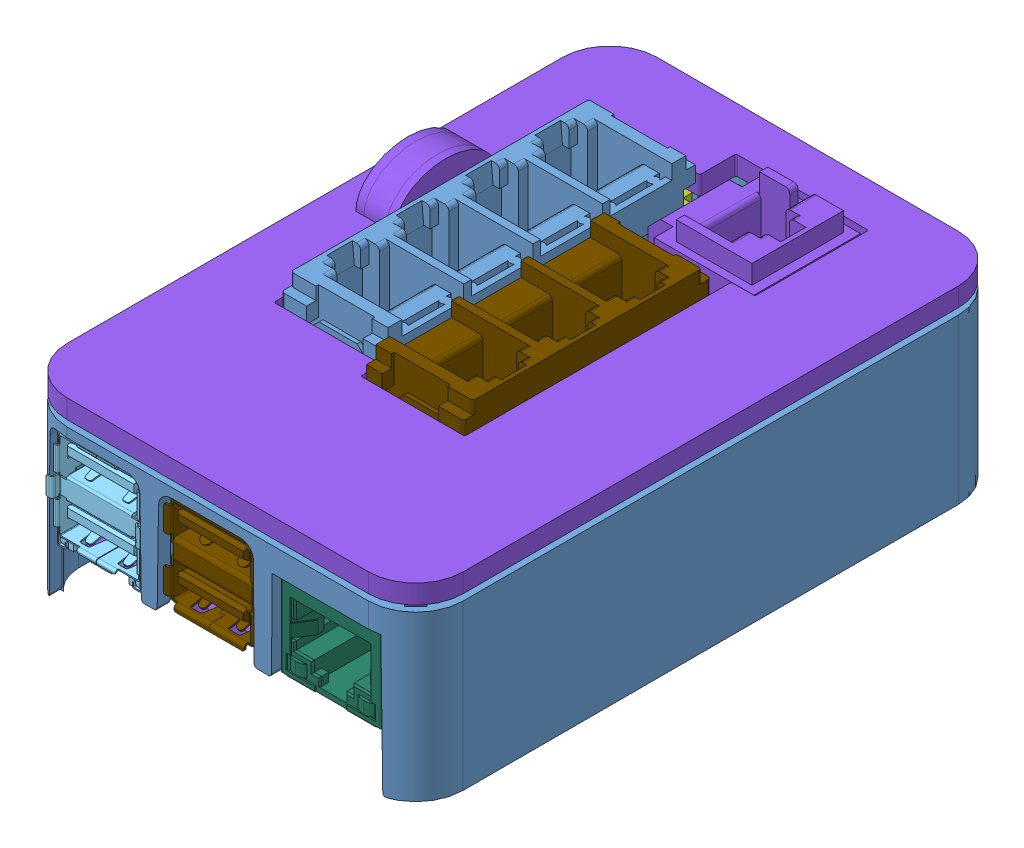
SolidWorks assembly Assemblage_clip_down, configuration Défaut. Lengths in mm.
Overall size (62.75 36.13 93.5).
237 component instances, 44 part files, 9 mates.
Components (placement in the parent):
- RPI4_Canakit_Case-1: RPI4_Canakit_Case [Défaut] at (-18.9096 -7.6584 0) size (62.75 26 93.5)
- Mainboard_Rpi4-1: Mainboard_Rpi4 [Défaut] at (4.6154 9.8935 -38.925) x (0 0 1) z (0 1 0) size (66 57.75 22.04)
  - Mainboard_Rpi4.step-1: Mainboard_Rpi4.step [Défaut] at origin size (66 57.75 22.04)
    - J5.step-1: J5.step [Défaut] at origin size (50.8 7.2 4.95)
      - m20-7812045_asm.step-1: m20-7812045_asm.step [Défaut] at (4.8701 0.0001 -1.7297) x (1 0 0) z (0 1 0) size (50.8 4.95 7.2)
        - M20-78120_MOULD.step-1: M20-78120_MOULD.step [Défaut] at origin size (50.8 4.95 5.08)
        - M20-781_CONTACT.step-1: M20-781_CONTACT.step [Défaut] at (-0.75 1.3 -2.135) size (1.5 2.8 2.83)
        - M20-781_CONTACT.step-2: M20-781_CONTACT.step [Défaut] at (1.79 1.3 -2.135) size (1.5 2.8 2.83)
        - M20-781_CONTACT.step-3: M20-781_CONTACT.step [Défaut] at (4.33 1.3 -2.135) size (1.5 2.8 2.83)
        - M20-781_CONTACT.step-4: M20-781_CONTACT.step [Défaut] at (6.87 1.3 -2.135) size (1.5 2.8 2.83)
        - M20-781_CONTACT.step-5: M20-781_CONTACT.step [Défaut] at (9.41 1.3 -2.135) size (1.5 2.8 2.83)
        - M20-781_CONTACT.step-6: M20-781_CONTACT.step [Défaut] at (11.95 1.3 -2.135) size (1.5 2.8 2.83)
        - M20-781_CONTACT.step-7: M20-781_CONTACT.step [Défaut] at (14.49 1.3 -2.135) size (1.5 2.8 2.83)
        - M20-781_CONTACT.step-8: M20-781_CONTACT.step [Défaut] at (17.03 1.3 -2.135) size (1.5 2.8 2.83)
        - M20-781_CONTACT.step-9: M20-781_CONTACT.step [Défaut] at (19.57 1.3 -2.135) size (1.5 2.8 2.83)
        - M20-781_CONTACT.step-10: M20-781_CONTACT.step [Défaut] at (22.11 1.3 -2.135) size (1.5 2.8 2.83)
        - M20-781_CONTACT.step-11: M20-781_CONTACT.step [Défaut] at (24.65 1.3 -2.135) size (1.5 2.8 2.83)
        - M20-781_CONTACT.step-12: M20-781_CONTACT.step [Défaut] at (27.19 1.3 -2.135) size (1.5 2.8 2.83)
        - M20-781_CONTACT.step-13: M20-781_CONTACT.step [Défaut] at (29.73 1.3 -2.135) size (1.5 2.8 2.83)
        - M20-781_CONTACT.step-14: M20-781_CONTACT.step [Défaut] at (32.27 1.3 -2.135) size (1.5 2.8 2.83)
        - M20-781_CONTACT.step-15: M20-781_CONTACT.step [Défaut] at (34.81 1.3 -2.135) size (1.5 2.8 2.83)
        - M20-781_CONTACT.step-16: M20-781_CONTACT.step [Défaut] at (37.35 1.3 -2.135) size (1.5 2.8 2.83)
        - M20-781_CONTACT.step-17: M20-781_CONTACT.step [Défaut] at (39.89 1.3 -2.135) size (1.5 2.8 2.83)
        - M20-781_CONTACT.step-18: M20-781_CONTACT.step [Défaut] at (42.43 1.3 -2.135) size (1.5 2.8 2.83)
        - M20-781_CONTACT.step-19: M20-781_CONTACT.step [Défaut] at (44.97 1.3 -2.135) size (1.5 2.8 2.83)
        - M20-781_CONTACT.step-20: M20-781_CONTACT.step [Défaut] at (47.51 1.3 -2.135) size (1.5 2.8 2.83)
        - M20-781_CONTACT.step-21: M20-781_CONTACT.step [Défaut] at (0.75 1.3 2.135) x (-1 0 0) z (0 0 -1) size (1.5 2.8 2.83)
        - M20-781_CONTACT.step-22: M20-781_CONTACT.step [Défaut] at (3.29 1.3 2.135) x (-1 0 0) z (0 0 -1) size (1.5 2.8 2.83)
        - M20-781_CONTACT.step-23: M20-781_CONTACT.step [Défaut] at (5.83 1.3 2.135) x (-1 0 0) z (0 0 -1) size (1.5 2.8 2.83)
        - M20-781_CONTACT.step-24: M20-781_CONTACT.step [Défaut] at (8.37 1.3 2.135) x (-1 0 0) z (0 0 -1) size (1.5 2.8 2.83)
        - M20-781_CONTACT.step-25: M20-781_CONTACT.step [Défaut] at (10.91 1.3 2.135) x (-1 0 0) z (0 0 -1) size (1.5 2.8 2.83)
        - M20-781_CONTACT.step-26: M20-781_CONTACT.step [Défaut] at (13.45 1.3 2.135) x (-1 0 0) z (0 0 -1) size (1.5 2.8 2.83)
        - M20-781_CONTACT.step-27: M20-781_CONTACT.step [Défaut] at (15.99 1.3 2.135) x (-1 0 0) z (0 0 -1) size (1.5 2.8 2.83)
        - M20-781_CONTACT.step-28: M20-781_CONTACT.step [Défaut] at (18.53 1.3 2.135) x (-1 0 0) z (0 0 -1) size (1.5 2.8 2.83)
        - M20-781_CONTACT.step-29: M20-781_CONTACT.step [Défaut] at (21.07 1.3 2.135) x (-1 0 0) z (0 0 -1) size (1.5 2.8 2.83)
        - M20-781_CONTACT.step-30: M20-781_CONTACT.step [Défaut] at (23.61 1.3 2.135) x (-1 0 0) z (0 0 -1) size (1.5 2.8 2.83)
        - M20-781_CONTACT.step-31: M20-781_CONTACT.step [Défaut] at (26.15 1.3 2.135) x (-1 0 0) z (0 0 -1) size (1.5 2.8 2.83)
        - M20-781_CONTACT.step-32: M20-781_CONTACT.step [Défaut] at (28.69 1.3 2.135) x (-1 0 0) z (0 0 -1) size (1.5 2.8 2.83)
        - M20-781_CONTACT.step-33: M20-781_CONTACT.step [Défaut] at (31.23 1.3 2.135) x (-1 0 0) z (0 0 -1) size (1.5 2.8 2.83)
        - M20-781_CONTACT.step-34: M20-781_CONTACT.step [Défaut] at (33.77 1.3 2.135) x (-1 0 0) z (0 0 -1) size (1.5 2.8 2.83)
        - M20-781_CONTACT.step-35: M20-781_CONTACT.step [Défaut] at (36.31 1.3 2.135) x (-1 0 0) z (0 0 -1) size (1.5 2.8 2.83)
        - M20-781_CONTACT.step-36: M20-781_CONTACT.step [Défaut] at (38.85 1.3 2.135) x (-1 0 0) z (0 0 -1) size (1.5 2.8 2.83)
        - M20-781_CONTACT.step-37: M20-781_CONTACT.step [Défaut] at (41.39 1.3 2.135) x (-1 0 0) z (0 0 -1) size (1.5 2.8 2.83)
        - M20-781_CONTACT.step-38: M20-781_CONTACT.step [Défaut] at (43.93 1.3 2.135) x (-1 0 0) z (0 0 -1) size (1.5 2.8 2.83)
        - M20-781_CONTACT.step-39: M20-781_CONTACT.step [Défaut] at (46.47 1.3 2.135) x (-1 0 0) z (0 0 -1) size (1.5 2.8 2.83)
        - M20-781_CONTACT.step-40: M20-781_CONTACT.step [Défaut] at (49.01 1.3 2.135) x (-1 0 0) z (0 0 -1) size (1.5 2.8 2.83)
    - C3.step-1: C3.step [Défaut] at origin size (2.2 1.45 1.4)
      - 870407824.step-1: 870407824.step [Défaut] at (-0.508 -11.732 -2.9519) size (2.2 1.45 1.4)
        - Extruded.step-1: Extruded.step [Défaut] at origin size (2.2 1.45 1.4)
    - C2.step-1: C2.step [Défaut] at origin size (2.2 1.45 1.4)
      - 870407824.step-1: 870407824.step [Défaut] at (50.8 -29.718 -2.9519) size (2.2 1.45 1.4)
        - Extruded.step-1: Extruded.step [Défaut] at origin size (2.2 1.45 1.4)
    - U10.step-1: U10.step [Défaut] at origin size (2 2 0.8)
      - 870408096.step-1: 870408096.step [Défaut] at (7.747 -16.873 -2.4519) size (2 2 0.8)
        - Extruded-0.step-1: Extruded-0.step [Défaut] at origin size (2 2 0.8)
    - U9.step-1: U9.step [Défaut] at origin size (2 2 0.8)
      - 870408096.step-1: 870408096.step [Défaut] at (11.049 -16.873 -2.4519) size (2 2 0.8)
        - Extruded-0.step-1: Extruded-0.step [Défaut] at origin size (2 2 0.8)
    - U8.step-1: U8.step [Défaut] at origin size (2 2 0.8)
      - 870408096.step-1: 870408096.step [Défaut] at (4.445 -16.873 -2.4519) size (2 2 0.8)
        - Extruded-0.step-1: Extruded-0.step [Défaut] at origin size (2 2 0.8)
    - R3.step-1: R3.step [Défaut] at origin size (1.4 2.15 0.7)
      - 870408368.step-1: 870408368.step [Défaut] at (8.89 -9.779 -2.2519) size (1.4 2.15 0.7)
        - Extruded-1.step-1: Extruded-1.step [Défaut] at origin size (1.4 2.15 0.7)
    - Q8.step-1: Q8.step [Défaut] at origin size (2.2 1.35 1)
      - 870406736.step-1: 870406736.step [Défaut] at (1.524 -8.938 -2.6519) size (2.2 1.35 1)
        - Extruded-2.step-1: Extruded-2.step [Défaut] at origin size (2.2 1.35 1)
    - J3.step-1: J3.step [Défaut] at origin size (20.9 19.8 19.5)
      - TM3RA-88_RGB13278208.step-1: TM3RA-88_RGB13278208.step [Défaut] at (8.2551 -24.0349 12.5) x (1 0 0) z (0 0 1) size (20.9 19.8 19.5)
    - U7.step-1: U7.step [Défaut] at origin size (2 2 0.8)
      - 870408096.step-1: 870408096.step [Défaut] at (26.369 -39.41 -2.4519) size (2 2 0.8)
        - Extruded-0.step-1: Extruded-0.step [Défaut] at origin size (2 2 0.8)
    - U6.step-1: U6.step [Défaut] at origin size (2 2 0.8)
      - 870408096.step-1: 870408096.step [Défaut] at (49.099 -15.349 -2.4519) size (2 2 0.8)
        - Extruded-0.step-1: Extruded-0.step [Défaut] at origin size (2 2 0.8)
    - U5.step-1: U5.step [Défaut] at origin size (2 2 0.8)
      - 870408096.step-1: 870408096.step [Défaut] at (37.291 -39.41 -2.4519) size (2 2 0.8)
        - Extruded-0.step-1: Extruded-0.step [Défaut] at origin size (2 2 0.8)
    - U4.step-1: U4.step [Défaut] at origin size (2 2 0.8)
      - 870408096.step-1: 870408096.step [Défaut] at (38.05 -15.349 -2.4519) size (2 2 0.8)
        - Extruded-0.step-1: Extruded-0.step [Défaut] at origin size (2 2 0.8)
    - U3.step-1: U3.step [Défaut] at origin size (2 2 0.8)
      - 870408096.step-1: 870408096.step [Défaut] at (15.32 -39.41 -2.4519) size (2 2 0.8)
        - Extruded-0.step-1: Extruded-0.step [Défaut] at origin size (2 2 0.8)
    - U2.step-1: U2.step [Défaut] at origin size (2 2 0.8)
      - 870408096.step-1: 870408096.step [Défaut] at (48.34 -39.41 -2.4519) size (2 2 0.8)
        - Extruded-0.step-1: Extruded-0.step [Défaut] at origin size (2 2 0.8)
    - U1.step-1: U1.step [Défaut] at origin size (2 2 0.8)
      - 870408096.step-1: 870408096.step [Défaut] at (27.128 -15.349 -2.4519) size (2 2 0.8)
        - Extruded-0.step-1: Extruded-0.step [Défaut] at origin size (2 2 0.8)
    - Q7.step-1: Q7.step [Défaut] at origin size (1.35 2.2 1)
      - 870407280.step-1: 870407280.step [Défaut] at (10.24 -39.16 -2.6519) size (1.35 2.2 1)
        - Extruded-3.step-1: Extruded-3.step [Défaut] at origin size (1.35 2.2 1)
    - Q6.step-1: Q6.step [Défaut] at origin size (1.35 2.2 1)
      - 870407280.step-1: 870407280.step [Défaut] at (21.289 -39.16 -2.6519) size (1.35 2.2 1)
        - Extruded-3.step-1: Extruded-3.step [Défaut] at origin size (1.35 2.2 1)
    - Q5.step-1: Q5.step [Défaut] at origin size (1.35 2.2 1)
      - 870407280.step-1: 870407280.step [Défaut] at (32.211 -39.16 -2.6519) size (1.35 2.2 1)
        - Extruded-3.step-1: Extruded-3.step [Défaut] at origin size (1.35 2.2 1)
    - Q4.step-1: Q4.step [Défaut] at origin size (1.35 2.2 1)
      - 870407280.step-1: 870407280.step [Défaut] at (43.26 -39.16 -2.6519) size (1.35 2.2 1)
        - Extruded-3.step-1: Extruded-3.step [Défaut] at origin size (1.35 2.2 1)
    - Q3.step-1: Q3.step [Défaut] at origin size (1.35 2.2 1)
      - 870407280.step-1: 870407280.step [Défaut] at (54.179 -15.599 -2.6519) size (1.35 2.2 1)
        - Extruded-3.step-1: Extruded-3.step [Défaut] at origin size (1.35 2.2 1)
    - Q2.step-1: Q2.step [Défaut] at origin size (1.35 2.2 1)
      - 870407280.step-1: 870407280.step [Défaut] at (43.13 -15.599 -2.6519) size (1.35 2.2 1)
        - Extruded-3.step-1: Extruded-3.step [Défaut] at origin size (1.35 2.2 1)
    - Q1.step-1: Q1.step [Défaut] at origin size (1.35 2.2 1)
      - 870407280.step-1: 870407280.step [Défaut] at (32.208 -15.599 -2.6519) size (1.35 2.2 1)
        - Extruded-3.step-1: Extruded-3.step [Défaut] at origin size (1.35 2.2 1)
    - R2.step-1: R2.step [Défaut] at origin size (2.15 1.4 0.7)
      - 870406464.step-1: 870406464.step [Défaut] at (43.514 -45.974 -2.2519) size (2.15 1.4 0.7)
        - Extruded-4.step-1: Extruded-4.step [Défaut] at origin size (2.15 1.4 0.7)
    - R1.step-1: R1.step [Défaut] at origin size (2.15 1.4 0.7)
      - 870406464.step-1: 870406464.step [Défaut] at (43.514 -48.26 -2.2519) size (2.15 1.4 0.7)
        - Extruded-4.step-1: Extruded-4.step [Défaut] at origin size (2.15 1.4 0.7)
    - U11.step-1: U11.step [Défaut] at origin size (4.91 6.03 1.75)
      - 873278928.step-1: 873278928.step [Défaut] at (0.635 -37.084 -1.5519) x (0 -1 0) z (0 0 -1) size (6.03 4.9 1.75)
        - Body.step-1: Body.step [Défaut] at (-1.95 -2.45 0) size (3.91 4.9 1.65)
          - Open_CASCADE_STEP_translator_6.8_10.2.1.step-1: Open_CASCADE_STEP_translator_6.8_10.2.1.step [Défaut] at origin size (3.91 4.9 1.65)
        - Open_CASCADE_STEP_translator_6.8_10.1.step-1: Open_CASCADE_STEP_translator_6.8_10.1.step [Défaut] at (-1.95 -2.45 0.001) size (0.5 0.5 0.01)
        - Leader.step-1: Leader.step [Défaut] at (-1.95 -1.905 0) x (-1 0 0) z (0 0 1) size (1.06 0.41 0.97)
        - Leader.step-2: Leader.step [Défaut] at (-1.95 -0.635 0) x (-1 0 0) z (0 0 1) size (1.06 0.41 0.97)
        - Leader.step-3: Leader.step [Défaut] at (-1.95 0.635 0) x (-1 0 0) z (0 0 1) size (1.06 0.41 0.97)
        - Leader.step-4: Leader.step [Défaut] at (-1.95 1.905 0) x (-1 0 0) z (0 0 1) size (1.06 0.41 0.97)
        - Leader.step-5: Leader.step [Défaut] at (1.95 -1.905 0) size (1.06 0.41 0.97)
        - Leader.step-6: Leader.step [Défaut] at (1.95 -0.635 0) size (1.06 0.41 0.97)
        - Leader.step-7: Leader.step [Défaut] at (1.95 0.635 0) size (1.06 0.41 0.97)
        - Leader.step-8: Leader.step [Défaut] at (1.95 1.905 0) size (1.06 0.41 0.97)
    - J4.step-1: J4.step [Défaut] at origin size (15.42 4.78 16.81)
      - BS-1225-PC.step-1: BS-1225-PC.step [Défaut] at (29.2101 -47.371 0) x (-1 0 0) z (0 1 0) size (15.42 16.81 4.78)
    - Cx2.step-1: Cx2.step [Défaut] at origin size (1.45 2.2 1.4)
      - 870404832.step-1: 870404832.step [Défaut] at (0.705 -26.66 -2.9519) size (1.45 2.2 1.4)
        - Extruded-5.step-1: Extruded-5.step [Défaut] at origin size (1.45 2.2 1.4)
    - Cx1.step-1: Cx1.step [Défaut] at origin size (1.45 2.2 1.4)
      - 870404832.step-1: 870404832.step [Défaut] at (-1.795 -26.66 -2.9519) size (1.45 2.2 1.4)
        - Extruded-5.step-1: Extruded-5.step [Défaut] at origin size (1.45 2.2 1.4)
    - C1.step-1: C1.step [Défaut] at origin size (2.2 1.45 1.4)
      - 870407824.step-1: 870407824.step [Défaut] at (-0.545 -42.926 -2.9519) size (2.2 1.45 1.4)
        - Extruded.step-1: Extruded.step [Défaut] at origin size (2.2 1.45 1.4)
    - U12.step-1: U12.step [Défaut] at origin size (3.7 2 0.9)
      - 873282384.step-1: 873282384.step [Défaut] at (-0.545 -30.9968 -1.5519) x (-1 0 0) z (0 0 -1) size (3.7 2 0.9)
        - Body-6.step-1: Body-6.step [Défaut] at (-1.65 -0.8 0) size (3.3 1.6 0.9)
        - bigPin.step-1: bigPin.step [Défaut] at (-1.85 -1 -0.0033) size (1.2 2 0.01)
        - bigPin.step-2: bigPin.step [Défaut] at (0.65 -1 -0.0033) size (1.2 2 0.01)
    - J1.step-1: J1.step [Défaut] at origin size (39.2 15.4 22.04)
      - TM2RE-1818(50)_RGB13278208.step-1: TM2RE-1818(50)_RGB13278208.step [Défaut] at (39.3359 -11.3181 16) x (1 0 0) z (0 0 1) size (39.2 15.4 22.04)
        - TM2RE-1818(50).step-1: TM2RE-1818(50).step [Défaut] at (0 -7.7 0) size (39.2 15.4 22.04)
    - J2.step-1: J2.step [Défaut] at origin size (50.2 15.4 22.04)
      - TM2RE-2424_RGB13278208.step-1: TM2RE-2424_RGB13278208.step [Défaut] at (47.0601 -35.774 16) x (-1 0 0) z (0 0 1) size (50.2 15.4 22.04)
    - P2.step-1: P2.step [Défaut] at origin size (2.54 2.54 5.55)
      - 870406192.step-1: 870406192.step [Défaut] at (0 -4.826 0) size (2.54 2.54 5.55)
        - Extruded-7.step-1: Extruded-7.step [Défaut] at origin size (2.54 2.54 5.55)
    - R4.step-1: R4.step [Défaut] at origin size (1.7 0.95 0.55)
      - 870422376.step-1: 870422376.step [Défaut] at (50.8 -27.7876 -2.1019) size (1.7 0.95 0.55)
        - Extruded-8.step-1: Extruded-8.step [Défaut] at origin size (1.7 0.95 0.55)
    - R5.step-1: R5.step [Défaut] at origin size (1.7 0.95 0.55)
      - 870422376.step-1: 870422376.step [Défaut] at (47.498 -27.7876 -2.1019) size (1.7 0.95 0.55)
        - Extruded-8.step-1: Extruded-8.step [Défaut] at origin size (1.7 0.95 0.55)
    - R6.step-1: R6.step [Défaut] at origin size (1.7 0.95 0.55)
      - 870422376.step-1: 870422376.step [Défaut] at (31.115 -12.7 -2.1019) size (1.7 0.95 0.55)
        - Extruded-8.step-1: Extruded-8.step [Défaut] at origin size (1.7 0.95 0.55)
    - R7.step-1: R7.step [Défaut] at origin size (1.7 0.95 0.55)
      - 870422376.step-1: 870422376.step [Défaut] at (26.162 -12.7 -2.1019) size (1.7 0.95 0.55)
        - Extruded-8.step-1: Extruded-8.step [Défaut] at origin size (1.7 0.95 0.55)
    - R8.step-1: R8.step [Défaut] at origin size (1.7 0.95 0.55)
      - 870422376.step-1: 870422376.step [Défaut] at (42.037 -12.7148 -2.1019) size (1.7 0.95 0.55)
        - Extruded-8.step-1: Extruded-8.step [Défaut] at origin size (1.7 0.95 0.55)
    - R9.step-1: R9.step [Défaut] at origin size (1.7 0.95 0.55)
      - 870422376.step-1: 870422376.step [Défaut] at (36.97 -12.7 -2.1019) size (1.7 0.95 0.55)
        - Extruded-8.step-1: Extruded-8.step [Défaut] at origin size (1.7 0.95 0.55)
    - R10.step-1: R10.step [Défaut] at origin size (1.7 0.95 0.55)
      - 870422376.step-1: 870422376.step [Défaut] at (52.844 -12.7148 -2.1019) size (1.7 0.95 0.55)
        - Extruded-8.step-1: Extruded-8.step [Défaut] at origin size (1.7 0.95 0.55)
    - R11.step-1: R11.step [Défaut] at origin size (1.7 0.95 0.55)
      - 870422376.step-1: 870422376.step [Défaut] at (48.073 -12.7 -2.1019) size (1.7 0.95 0.55)
        - Extruded-8.step-1: Extruded-8.step [Défaut] at origin size (1.7 0.95 0.55)
    - R12.step-1: R12.step [Défaut] at origin size (1.7 0.95 0.55)
      - 870422376.step-1: 870422376.step [Défaut] at (43.815 -41.402 -2.1019) size (1.7 0.95 0.55)
        - Extruded-8.step-1: Extruded-8.step [Défaut] at origin size (1.7 0.95 0.55)
    - R13.step-1: R13.step [Défaut] at origin size (1.7 0.95 0.55)
      - 870422376.step-1: 870422376.step [Défaut] at (49.093 -42.585 -2.1019) size (1.7 0.95 0.55)
        - Extruded-8.step-1: Extruded-8.step [Défaut] at origin size (1.7 0.95 0.55)
    - R14.step-1: R14.step [Défaut] at origin size (1.7 0.95 0.55)
      - 870422376.step-1: 870422376.step [Défaut] at (32.766 -41.402 -2.1019) size (1.7 0.95 0.55)
        - Extruded-8.step-1: Extruded-8.step [Défaut] at origin size (1.7 0.95 0.55)
    - R15.step-1: R15.step [Défaut] at origin size (1.7 0.95 0.55)
      - 870422376.step-1: 870422376.step [Défaut] at (38.044 -42.2262 -2.1019) size (1.7 0.95 0.55)
        - Extruded-8.step-1: Extruded-8.step [Défaut] at origin size (1.7 0.95 0.55)
    - R16.step-1: R16.step [Défaut] at origin size (1.7 0.95 0.55)
      - 870422376.step-1: 870422376.step [Défaut] at (21.857 -41.402 -2.1019) size (1.7 0.95 0.55)
        - Extruded-8.step-1: Extruded-8.step [Défaut] at origin size (1.7 0.95 0.55)
    - R17.step-1: R17.step [Défaut] at origin size (1.7 0.95 0.55)
      - 870422376.step-1: 870422376.step [Défaut] at (27.122 -42.2262 -2.1019) size (1.7 0.95 0.55)
        - Extruded-8.step-1: Extruded-8.step [Défaut] at origin size (1.7 0.95 0.55)
    - R18.step-1: R18.step [Défaut] at origin size (1.7 0.95 0.55)
      - 870422376.step-1: 870422376.step [Défaut] at (10.821 -41.402 -2.1019) size (1.7 0.95 0.55)
        - Extruded-8.step-1: Extruded-8.step [Défaut] at origin size (1.7 0.95 0.55)
    - R19.step-1: R19.step [Défaut] at origin size (1.7 0.95 0.55)
      - 870422376.step-1: 870422376.step [Défaut] at (16.073 -42.2262 -2.1019) size (1.7 0.95 0.55)
        - Extruded-8.step-1: Extruded-8.step [Défaut] at origin size (1.7 0.95 0.55)
    - R20.step-1: R20.step [Défaut] at origin size (0.95 1.7 0.55)
      - 870405920.step-1: 870405920.step [Défaut] at (13.2927 -21.987 -2.1019) size (0.95 1.7 0.55)
        - Extruded-9.step-1: Extruded-9.step [Défaut] at origin size (0.95 1.7 0.55)
    - R21.step-1: R21.step [Défaut] at origin size (0.95 1.7 0.55)
      - 870405920.step-1: 870405920.step [Défaut] at (14.986 -21.987 -2.1019) size (0.95 1.7 0.55)
        - Extruded-9.step-1: Extruded-9.step [Défaut] at origin size (0.95 1.7 0.55)
    - U13.step-1: U13.step [Défaut] at origin size (8.49 8.49 1)
      - 870411632.step-1: 870411632.step [Défaut] at (17.055 -9.1329 -2.5519) size (8.49 8.49 1)
        - Extruded-10.step-1: Extruded-10.step [Défaut] at origin size (8.49 8.49 1)
    - Free-Models.step-1: Free-Models.step [Défaut] at origin size (12.5 1.6 12.5)
      - 873281360.step-1: 873281360.step [Défaut] at (29.21 -48.336 7.5) x (-1 0 0) z (0 1 0) size (12.5 12.5 1.6)
        - Cylinder.step-1: Cylinder.step [Défaut] at origin size (12.5 12.5 1.6)
    - Board.step-1: Board.step [Défaut] at (0 0 -1.5519) size (66 57.75 1.55)
- Raspberry Pi 4 Model B-1: Raspberry Pi 4 Model B [Défaut] at (-19.8846 -0.4584 0.075) x (0 0 1) z (-1 0 0) size (89 19.92 58.4)
  - Raspberry Pi 4 Model B.STEP-1: Raspberry Pi 4 Model B.STEP [Défaut] at origin size (89 19.92 58.4)
    - PCB, RPi4ModelB.STEP-1: PCB, RPi4ModelB.STEP [Défaut] at origin size (85 1.6 56)
    - Broadcom BCM2711B0 CPU, RPi4ModelB.STEP-1: Broadcom BCM2711B0 CPU, RPi4ModelB.STEP [Défaut] at (-13.25 0.8 -4.5) size (15 2.3 15)
    - 2.54 mm DUPONT MALE PIN HEADER, POE, 2X2, RPi4ModelB.STEP-1: 2.54 mm DUPONT MALE PIN HEADER, POE, 2X2, RPi4ModelB.STEP [Défaut] at (19 0.8 -18.36) size (5.08 11.3 5.08)
    - 2.54 mm DUPONT MALE PIN HEADER, IO, 2X20, RPi4ModelB.STEP-1: 2.54 mm DUPONT MALE PIN HEADER, IO, 2X20, RPi4ModelB.STEP [Défaut] at (-10 0.8 -24.5) size (50.8 11.3 5.08)
    - Camera Connector, RPi4ModelB.STEP-1: Camera Connector, RPi4ModelB.STEP [Défaut] at (4 0.8 16.5) x (0 0 -1) z (1 0 0) size (22.4 5.68 5.07)
    - Microphone Plug, RPi4ModelB.STEP-1: Microphone Plug, RPi4ModelB.STEP [Défaut] at (11.5 0.8 21.65) size (7.23 7.55 15)
    - Display Connector, RPi4ModelB.STEP-1: Display Connector, RPi4ModelB.STEP [Défaut] at (-38.5 0.8 0) x (0 0 1) z (-1 0 0) size (22.4 5.68 5.07)
    - Gigabit Ethernet Port, RPi4ModelB.STEP-1: Gigabit Ethernet Port, RPi4ModelB.STEP [Défaut] at (45.5 7.55 -17.75) x (0 0 -1) z (1 0 0) size (16.33 17.24 21.6)
    - Female Micro HDMI Connector, RPi4ModelB.STEP-1: Female Micro HDMI Connector, RPi4ModelB.STEP [Défaut] at (-3 0.8 27.3875) size (6.5 3.51 7.5)
    - Female Micro HDMI Connector, RPi4ModelB.STEP-2: Female Micro HDMI Connector, RPi4ModelB.STEP [Défaut] at (-16.5 0.8 27.3875) size (6.5 3.51 7.5)
    - Female USB Type C Connector, RPi4ModelB.STEP-1: Female USB Type C Connector, RPi4ModelB.STEP [Défaut] at (-31.3 0.8 26.5419) size (8.94 3.96 7.9)
    - 2X USB3.0 PORTS, RPi4ModelB.STEP-1: 2X USB3.0 PORTS, RPi4ModelB.STEP [Défaut] at (37.07 0.8 1) size (17.48 19.42 15.69)
    - 91D77 D9WHV 778K, 4 GB LPDDR4 SDRAM, RPi4ModelB.STEP-1: 91D77 D9WHV 778K, 4 GB LPDDR4 SDRAM, RPi4ModelB.STEP [Défaut] at (2.25 0.8 -4.5) size (10 0.8 14.5)
    - Cypress CYW43455 Wireless Module Cover, RPi4ModelB.STEP-1: Cypress CYW43455 Wireless Module Cover, RPi4ModelB.STEP [Défaut] at (-30.5 0.8 -14.5) size (11 1.6 13)
    - SD Card Slot, RPi4ModelB.STEP-1: SD Card Slot, RPi4ModelB.STEP [Défaut] at (-35.3 -0.8 0) x (0 0 -1) z (-1 0 0) size (11.95 1.45 11.4)
    - VIA VL805 PCIe USB 3.0 controller, RPi4ModelB.STEP-1: VIA VL805 PCIe USB 3.0 controller, RPi4ModelB.STEP [Défaut] at (17.5 0.8 4) size (8.8 0.8 8.8)
    - 2X USB2.0 PORTS, RPi4ModelB.STEP-1: 2X USB2.0 PORTS, RPi4ModelB.STEP [Défaut] at (37.065 0.65 19) size (17.87 19.17 15.35)
    - Broadcom BCM54213PE Gigabit Ethernet Transceiver, RPi4ModelB.STEP-1: Broadcom BCM54213PE Gigabit Ethernet Transceiver, RPi4ModelB.STEP [Défaut] at (16.5 0.8 -10) size (6.8 1 6.8)
    - MxL7704 Universal PMIC, RPi4ModelB.STEP-1: MxL7704 Universal PMIC, RPi4ModelB.STEP [Défaut] at (-32.5 0.8 16) size (5.4 0.8 5.4)
- RPI4_Canakit_cover_clip_down-1: RPI4_Canakit_cover_clip_down [Défaut] at (-18.9096 20.8416 0) x (-1 0 0) z (0 0 1) size (62.75 15.93 93.5)
Mates (geometry in assembly coordinates):
- Coaxiale1: concentric aligned: cylinder of RPI4_Canakit_Case-1 through (12.4664 3.3416 11.575) axis (-1 0 0) radius 3.5; cylinder of Raspberry Pi 4 Model B-1/Raspberry Pi 4 Model B.STEP-1/Microphone Plug, RPi4ModelB.STEP-1 through (-47.7846 3.3416 11.575) axis (-1 0 0) radius 3
- Parallèle1: parallel aligned: plane of RPI4_Canakit_Case-1 through (-18.9096 -7.6584 0) normal (0 -1 0); plane of Raspberry Pi 4 Model B-1/Raspberry Pi 4 Model B.STEP-1/PCB, RPi4ModelB.STEP-1 through (-19.8846 -1.2584 0.075) normal (0 -1 0)
- Coïncidente4: coincident aligned: plane of RPI4_Canakit_Case-1 through (-50.2846 18.3416 -46.75) normal (-1 0 0); plane of Raspberry Pi 4 Model B-1/Raspberry Pi 4 Model B.STEP-1/Microphone Plug, RPi4ModelB.STEP-1 through (-50.2846 0.6406 8.874) normal (-1 0 0)
- Coaxiale2: concentric anti-aligned: cylinder of Mainboard_Rpi4-1/Mainboard_Rpi4.step-1/Board.step-1 through (4.6154 8.3416 19.075) axis (0 -1 0) radius 1.375; cylinder of Raspberry Pi 4 Model B-1/Raspberry Pi 4 Model B.STEP-1/PCB, RPi4ModelB.STEP-1 through (4.6154 0.3416 19.075) axis (0 1 0) radius 1.35
- Parallèle3: parallel anti-aligned: plane of RPI4_Canakit_Case-1 through (10.4654 -7.6594 -39.25) normal (-1 0 0); plane of Mainboard_Rpi4-1/Mainboard_Rpi4.step-1/Board.step-1 through (9.8654 8.3416 16.575) normal (1 0 0)
- Coïncidente7: coincident anti-aligned: plane of RPI4_Canakit_Case-1 through (-42.7846 8.3416 -39.25) normal (0 1 0); plane of Mainboard_Rpi4-1/Mainboard_Rpi4.step-1/Board.step-1 through (-47.8846 8.3416 -38.425) normal (0 -1 0)
- Distance1: distance = 1 mm anti-aligned: plane of RPI4_Canakit_Case-1 through (-18.9096 18.3416 0) normal (0 1 0); plane of RPI4_Canakit_cover_clip_down-1 through (4.9654 19.3416 39.25) normal (0 -1 0)
- Largeur1: width anti-aligned: plane of RPI4_Canakit_cover_clip_down-1 through (-50.2846 19.3416 39.25) normal (-1 0 0); plane of RPI4_Canakit_Case-1 through (12.4654 19.3416 39.25) normal (1 0 0); plane of RPI4_Canakit_cover_clip_down-1 through (12.4654 18.3416 -46.75) normal (1 0 0); plane of RPI4_Canakit_Case-1 through (-50.2846 18.3416 -46.75) normal (-1 0 0)
- Largeur2: width anti-aligned: plane of RPI4_Canakit_cover_clip_down-1 through (4.9654 19.3416 -46.75) normal (0 0 -1); plane of RPI4_Canakit_Case-1 through (4.9654 19.3416 46.75) normal (0 0 1); plane of RPI4_Canakit_cover_clip_down-1 through (-50.2846 18.3416 46.75) normal (0 0 1); plane of RPI4_Canakit_Case-1 through (-50.2846 18.3416 -46.75) normal (0 0 -1)
